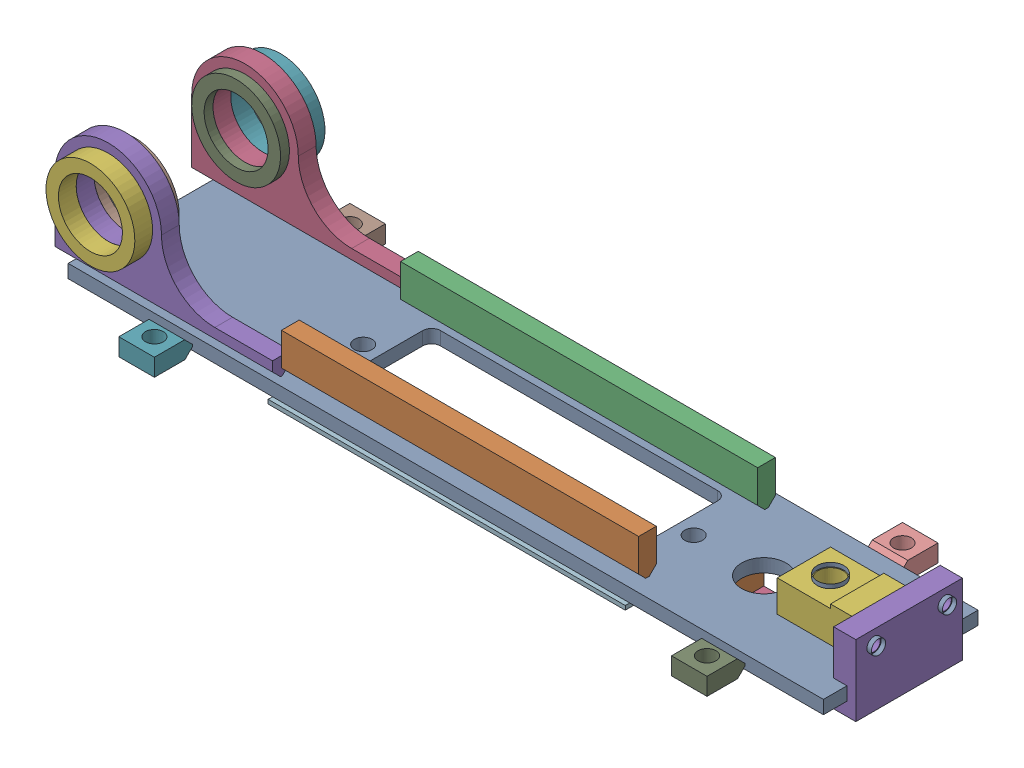
SolidWorks assembly g1_3_1_1_6_2, configuration 默认. Lengths in mm.
Overall size (880 200 260).
23 component instances, 19 part files, 0 mates.
Components (placement in the parent):
- g1_3_1_1_6-4_af0_2-1: g1_3_1_1_6-4_af0_2 [默认] at origin size (850 15 174)
- g1_3_1_1_6-8_2-1: g1_3_1_1_6-8_2 [默认] at (0 40 57) x (1 0 0) z (0 -1 0) size (402 20 44.8)
- g1_3_1_1_6-8_2-2: g1_3_1_1_6-8_2 [默认] at (0 40 -77) x (1 0 0) z (0 -1 0) size (402 20 44.8)
- g1_3_1_1_6-1_2-1: g1_3_1_1_6-1_2 [默认] at (-386 95 -87) x (1 0 0) z (0 -1 0) size (245 20 140)
- g1_3_1_1_6-1_2-2: g1_3_1_1_6-1_2 [默认] at (-386 95 67) x (1 0 0) z (0 -1 0) size (245 20 140)
- g1_3_1_1_6-3_2-1: g1_3_1_1_6-3_2 [默认] at (-386 95 87) x (-1 0 0) z (0 1 0) size (100 20 100)
- g1_3_1_1_6-3_2-2: g1_3_1_1_6-3_2 [默认] at (-386 95 -107) x (-1 0 0) z (0 1 0) size (100 20 100)
- g1_3_1_1_6-2_2-1: g1_3_1_1_6-2_2 [默认] at (-386 95 57) x (-1 0 0) z (0 1 0) size (100 10 100)
- g1_3_1_1_6-2_2-2: g1_3_1_1_6-2_2 [默认] at (-386 95 -57) x (1 0 0) z (0 1 0) size (100 10 100)
- g1_3_1_1_6-6_af1_2-1: g1_3_1_1_6-6_af1_2 [默认] at (186 -5 0) x (0 0 -1) z (1 0 0) size (130 4.6 30)
- g1_3_1_1_6-6_af0_2-1: g1_3_1_1_6-6_af0_2 [默认] at (-186 -5 0) x (0 0 -1) z (1 0 0) size (130 4.6 30)
- g1_3_1_1_6-7_af0_2-1: g1_3_1_1_6-7_af0_2 [默认] at (0 0 78.5) x (1 0 0) z (0 0 -1) size (402 4.6 27)
- g1_3_1_1_6-7_af1_2-1: g1_3_1_1_6-7_af1_2 [默认] at (0 -5 -78.5) size (402 4.6 27)
- g1_3_1_1_6-9_2-1: g1_3_1_1_6-9_2 [默认] at (220 -17 0) x (0 1 0) z (0 0 -1) size (35 15 60)
- g1_3_1_1_6-9_af0_2-1: g1_3_1_1_6-9_af0_2 [默认] at (310 -17 0) x (0 1 0) z (0 0 1) size (35 15 60)
- g1_3_1_1_6-10_2-1: g1_3_1_1_6-10_2 [默认] at (265 -45 0) size (60 20 60)
- g1_3_1_1_6-12_af0_2-1: g1_3_1_1_6-12_af0_2 [默认] at (434 25 0.5) x (0 0 1) z (0 -1 0) size (120 25 80)
- g1_3_1_1_6-11_af0_2-1: g1_3_1_1_6-11_af0_2 [默认] at (357 15 0) size (94 40 60)
- g1_3_1_1_6-5_af0_2-1: g1_3_1_1_6-5_af0_2 [默认] at (-311 -5 108.5) x (0 0 -1) z (1 0 0) size (43 19.6 40)
- g1_3_1_1_6-5_af1_2-1: g1_3_1_1_6-5_af1_2 [默认] at (-311 -5 -108.5) x (0 0 1) z (-1 0 0) size (43 19.6 40)
- g1_3_1_1_6-5_af2_2-1: g1_3_1_1_6-5_af2_2 [默认] at (311 -5 108.5) x (0 0 -1) z (1 0 0) size (43 19.6 40)
- g1_3_1_1_6-5_af3_2-1: g1_3_1_1_6-5_af3_2 [默认] at (311 -5 -108.5) x (0 0 1) z (-1 0 0) size (43 19.6 40)
- g1_3_1_1_6_more_2-1: g1_3_1_1_6_more_2 [默认] at origin size (109 70.2 96)
